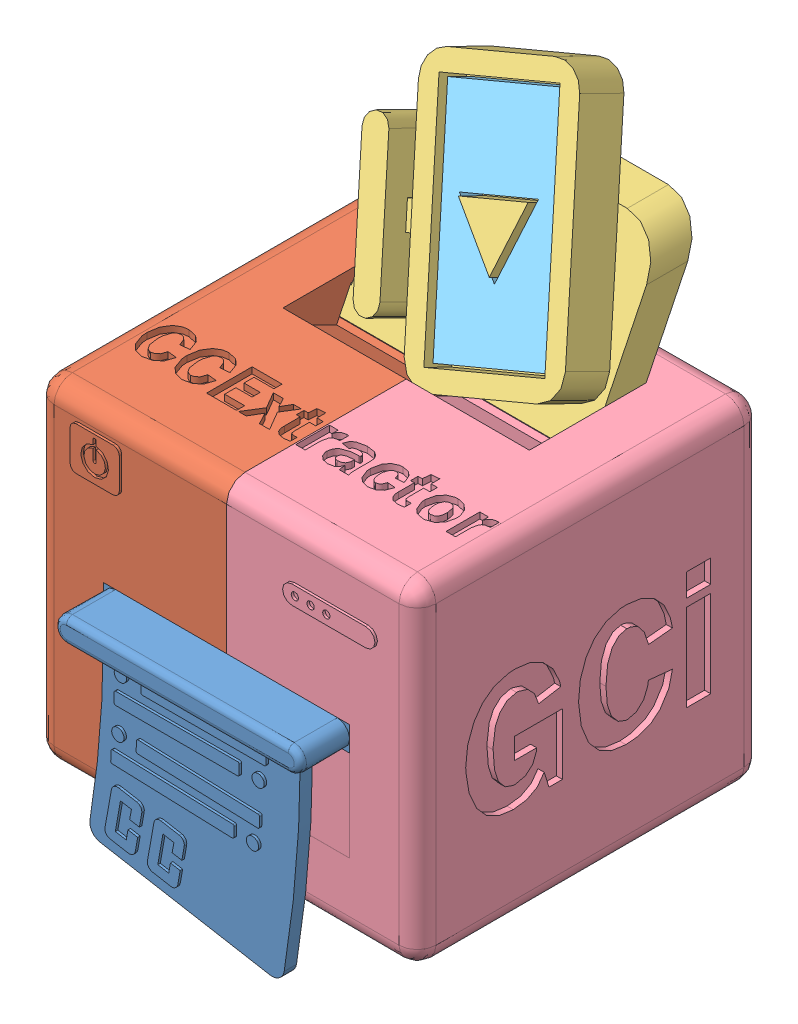
SolidWorks assembly [A] Static-Multi Color Swap Filament, configuration Default. Lengths in mm.
Overall size (393.7 623.14 418.41).
5 component instances, 5 part files, 12 mates.
Components (placement in the parent):
- [P] Static-Multi Color Swap Filament - Bill and Script-1: [P] Static-Multi Color Swap Filament - Bill and Script [Default] at (215.9344 -170.3006 -230.9464) size (304.8 302.72 90.8)
- [P] Static-Multi Color Swap Filament - Main Body Left-2: [P] Static-Multi Color Swap Filament - Main Body Left [Default] at (215.9344 -170.3006 -230.9464) size (196.85 342.9 358.14)
- [P] Static-Multi Color Swap Filament - Tray and TV-2: [P] Static-Multi Color Swap Filament - Tray and TV [Default] at (215.9344 -170.962 -232.2927) size (304.8 285.99 169.29)
- [P] Static-Multi Color Swap Filament - Main Body Right-2: [P] Static-Multi Color Swap Filament - Main Body Right [Default] at (210.8544 -170.3006 -230.9464) size (245.11 342.9 358.14)
- [P] Static-Multi Color Swap Filament - TV Plate-2: [P] Static-Multi Color Swap Filament - TV Plate [Default] at (230.2306 266.0374 -163.1188) x (0.34202 -0.843414 0.414337) z (-0.939693 -0.306977 0.150806) size (209.55 25.4 107.95)
Mates (geometry in assembly coordinates):
- Coincident1: coincident anti-aligned: plane of [P] Static-Multi Color Swap Filament - Bill and Script-1 through (19.0844 83.6994 109.6536) normal (0 1 0); plane of [P] Static-Multi Color Swap Filament - Main Body Left-2 through (-38.1398 83.6994 84.6536) normal (0 -1 0)
- Coincident2: coincident anti-aligned: plane of [P] Static-Multi Color Swap Filament - Bill and Script-1 through (19.0844 20.1994 109.6536) normal (0 0 1); plane of [P] Static-Multi Color Swap Filament - Main Body Left-2 through (-38.1398 83.6994 109.6536) normal (0 0 -1)
- Coincident3: coincident anti-aligned: plane of [P] Static-Multi Color Swap Filament - Bill and Script-1 through (63.5344 -170.3006 -230.9464) normal (-1 0 0); plane of [P] Static-Multi Color Swap Filament - Main Body Left-2 through (63.5344 -170.3006 -230.9464) normal (1 0 0)
- Coincident4: coincident anti-aligned: plane of [P] Static-Multi Color Swap Filament - Main Body Left-2 through (-129.7558 122.3632 -145.5151) normal (0 0.897542 -0.440929); plane of [P] Static-Multi Color Swap Filament - Tray and TV-2 through (19.0844 121.7018 -146.8614) normal (0 -0.897542 0.440929)
- Coincident5: coincident anti-aligned: plane of [P] Static-Multi Color Swap Filament - Main Body Left-2 through (27.642 118.1303 -154.1315) normal (0 0.440929 0.897542); plane of [P] Static-Multi Color Swap Filament - Tray and TV-2 through (342.9344 171.938 -180.5652) normal (0 -0.440929 -0.897542)
- Coincident6: coincident anti-aligned: plane of [P] Static-Multi Color Swap Filament - Main Body Left-2 through (63.5344 -170.3006 -230.9464) normal (1 0 0); plane of [P] Static-Multi Color Swap Filament - Tray and TV-2 through (63.5344 -170.962 -232.2927) normal (-1 0 0)
- Concentric1: concentric: cylinder of [P] Static-Multi Color Swap Filament - Main Body Left-2 through (162.5944 139.9038 91.9579) axis (1 0 0) radius 25.4; cylinder of [P] Static-Multi Color Swap Filament - Main Body Right-2 through (528.1726 139.9038 91.9579) axis (1 0 0) radius 25.4
- Concentric2: concentric: cylinder of [P] Static-Multi Color Swap Filament - Main Body Left-2 through (162.5944 -137.605 -198.2508) axis (1 0 0) radius 25.4; cylinder of [P] Static-Multi Color Swap Filament - Main Body Right-2 through (528.1726 -137.605 -198.2508) axis (1 0 0) radius 25.4
- Width1: width anti-aligned: plane of [P] Static-Multi Color Swap Filament - TV Plate-2 through (143.6755 349.0365 -175.5936) normal (-0.939693 -0.306977 0.150806); plane of [P] Static-Multi Color Swap Filament - TV Plate-2 through (316.7857 205.4374 -105.0488) normal (0.939693 0.306977 -0.150806); plane of [P] Static-Multi Color Swap Filament - Tray and TV-2 through (139.6061 350.7397 -176.4303) normal (0.939693 0.306977 -0.150806); plane of [P] Static-Multi Color Swap Filament - Tray and TV-2 through (247.013 385.8273 -193.6675) normal (-0.939693 -0.306977 0.150806)
- Width2: width aligned: plane of [P] Static-Multi Color Swap Filament - TV Plate-2 through (215.3458 172.2992 -88.7692) normal (0.34202 -0.843414 0.414337); plane of [P] Static-Multi Color Swap Filament - TV Plate-2 through (245.1153 382.1748 -191.8732) normal (-0.34202 0.843414 -0.414337); plane of [P] Static-Multi Color Swap Filament - Tray and TV-2 through (139.6061 350.7397 -176.4303) normal (0.34202 -0.843414 0.414337); plane of [P] Static-Multi Color Swap Filament - Tray and TV-2 through (213.4482 168.6467 -86.9749) normal (-0.34202 0.843414 -0.414337)
- Coincident7: coincident anti-aligned: plane of [P] Static-Multi Color Swap Filament - Tray and TV-2 through (215.9344 -58.6257 -3.624) normal (0 0.440929 0.897542); plane of [P] Static-Multi Color Swap Filament - TV Plate-2 through (230.2306 266.0374 -163.1188) normal (0 -0.440929 -0.897542)
- Coincident8: coincident anti-aligned: plane of [P] Static-Multi Color Swap Filament - Main Body Left-2 through (215.9344 -170.3006 -230.9464) normal (1 0 0); plane of [P] Static-Multi Color Swap Filament - Main Body Right-2 through (215.9344 -170.3006 -230.9464) normal (-1 0 0)
